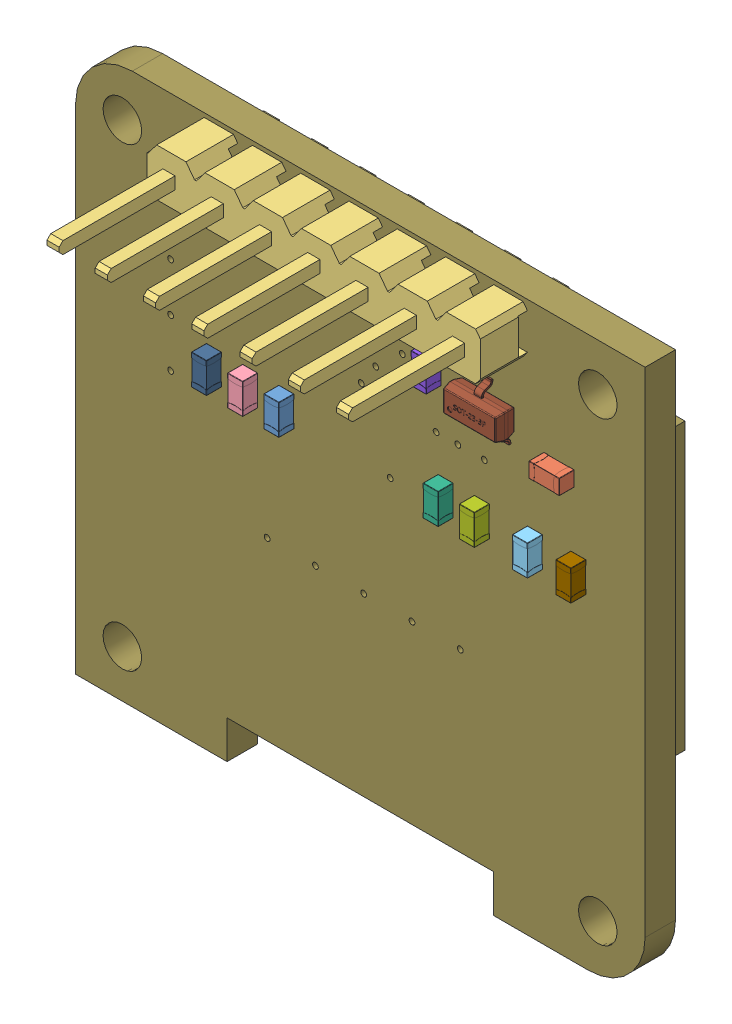
SolidWorks assembly OLED, configuration 默认. Lengths in mm.
Overall size (29.97 28.97 13.2).
35 component instances, 12 part files, 0 mates.
Components (placement in the parent):
- 3D_PCB_7针SPI_2022-02-05_2022-02-05(2)^OLED-1: 3D_PCB_7针SPI_2022-02-05_2022-02-05(2)^OLED [默认] at origin size (29.97 28.97 13.2) (virtual)
  - R5(2)^3D_PCB_7针SPI_2022-02-05_2022-02-05(2)_OLED-1: R5(2)^3D_PCB_7针SPI_2022-02-05_2022-02-05(2)_OLED [默认] at (11.176 -11.303 1.6) x (0 -1 0) z (0 0 1) size (1.6 0.8 0.8) (virtual)
    - R0603^R5(2)_3D_PCB_7针SPI_2022-02-05_2022-02-05(2)_OLED-1: R0603^R5(2)_3D_PCB_7针SPI_2022-02-05_2022-02-05(2)_OLED [默认] at origin size (1.6 0.8 0.8) (virtual)
      - =_[0_1_1_5]^R0603_R5(2)_3D_PCB_7针SPI_2022-02-05_2022-02-05(2)_OLED-1: =_[0_1_1_5]^R0603_R5(2)_3D_PCB_7针SPI_2022-02-05_2022-02-05(2)_OLED [默认] at (0 0 0.4) size (1.6 0.8 0.8) (virtual)
  - R6(2)^3D_PCB_7针SPI_2022-02-05_2022-02-05(2)_OLED-1: R6(2)^3D_PCB_7针SPI_2022-02-05_2022-02-05(2)_OLED [默认] at (25.5271 -6.985 1.6) x (-1 0 0) z (0 0 1) size (1.6 0.8 0.8) (virtual)
    - R0603^R6(2)_3D_PCB_7针SPI_2022-02-05_2022-02-05(2)_OLED-1: R0603^R6(2)_3D_PCB_7针SPI_2022-02-05_2022-02-05(2)_OLED [默认] at origin size (1.6 0.8 0.8) (virtual)
      - =_[0_1_1_5]^R0603_R6(2)_3D_PCB_7针SPI_2022-02-05_2022-02-05(2)_OLED-1: =_[0_1_1_5]^R0603_R6(2)_3D_PCB_7针SPI_2022-02-05_2022-02-05(2)_OLED [默认] at (0 0 0.4) size (1.6 0.8 0.8) (virtual)
  - J1^3D_PCB_7针SPI_2022-02-05_2022-02-05(2)_OLED-1: J1^3D_PCB_7针SPI_2022-02-05_2022-02-05(2)_OLED [默认] at (15.113 -1.524 1.6) size (17.53 2.5 11.6) (virtual)
    - HDR-M-2.54_1X7^J1_3D_PCB_7针SPI_2022-02-05_2022-02-05(2)_OLED-1: HDR-M-2.54_1X7^J1_3D_PCB_7针SPI_2022-02-05_2022-02-05(2)_OLED [默认] at origin size (17.53 2.5 11.6) (virtual)
      - =_[0_1_1_10]^HDR-M-2.54_1X7_J1_3D_PCB_7针SPI_2022-02-05_2022-02-05(2)_OLED-1: =_[0_1_1_10]^HDR-M-2.54_1X7_J1_3D_PCB_7针SPI_2022-02-05_2022-02-05(2)_OLED [默认] at origin size (17.53 2.5 11.6) (virtual)
  - C5(2)^3D_PCB_7针SPI_2022-02-05_2022-02-05(2)_OLED-1: C5(2)^3D_PCB_7针SPI_2022-02-05_2022-02-05(2)_OLED [默认] at (9.271 -11.303 1.6) x (0 -1 0) z (0 0 1) size (1.6 0.8 0.8) (virtual)
    - C0603^C5(2)_3D_PCB_7针SPI_2022-02-05_2022-02-05(2)_OLED-1: C0603^C5(2)_3D_PCB_7针SPI_2022-02-05_2022-02-05(2)_OLED [默认] at origin size (1.6 0.8 0.8) (virtual)
      - =_[0_1_1_14]^C0603_C5(2)_3D_PCB_7针SPI_2022-02-05_2022-02-05(2)_OLED-1: =_[0_1_1_14]^C0603_C5(2)_3D_PCB_7针SPI_2022-02-05_2022-02-05(2)_OLED [默认] at (0 0 0.4) size (1.6 0.8 0.8) (virtual)
  - C2(2)^3D_PCB_7针SPI_2022-02-05_2022-02-05(2)_OLED-1: C2(2)^3D_PCB_7针SPI_2022-02-05_2022-02-05(2)_OLED [默认] at (24.257 -11.176 1.6) x (0 -1 0) z (0 0 1) size (1.6 0.8 0.8) (virtual)
    - C0603^C2(2)_3D_PCB_7针SPI_2022-02-05_2022-02-05(2)_OLED-1: C0603^C2(2)_3D_PCB_7针SPI_2022-02-05_2022-02-05(2)_OLED [默认] at origin size (1.6 0.8 0.8) (virtual)
      - =_[0_1_1_14]^C0603_C2(2)_3D_PCB_7针SPI_2022-02-05_2022-02-05(2)_OLED-1: =_[0_1_1_14]^C0603_C2(2)_3D_PCB_7针SPI_2022-02-05_2022-02-05(2)_OLED [默认] at (0 0 0.4) size (1.6 0.8 0.8) (virtual)
  - C3(2)^3D_PCB_7针SPI_2022-02-05_2022-02-05(2)_OLED-1: C3(2)^3D_PCB_7针SPI_2022-02-05_2022-02-05(2)_OLED [默认] at (19.558 -11.176 1.6) x (0 1 0) z (0 0 1) size (1.6 0.8 0.8) (virtual)
    - C0603^C3(2)_3D_PCB_7针SPI_2022-02-05_2022-02-05(2)_OLED-1: C0603^C3(2)_3D_PCB_7针SPI_2022-02-05_2022-02-05(2)_OLED [默认] at origin size (1.6 0.8 0.8) (virtual)
      - =_[0_1_1_14]^C0603_C3(2)_3D_PCB_7针SPI_2022-02-05_2022-02-05(2)_OLED-1: =_[0_1_1_14]^C0603_C3(2)_3D_PCB_7针SPI_2022-02-05_2022-02-05(2)_OLED [默认] at (0 0 0.4) size (1.6 0.8 0.8) (virtual)
  - C4(2)^3D_PCB_7针SPI_2022-02-05_2022-02-05(2)_OLED-1: C4(2)^3D_PCB_7针SPI_2022-02-05_2022-02-05(2)_OLED [默认] at (21.463 -11.176 1.6) x (0 1 0) z (0 0 1) size (1.6 0.8 0.8) (virtual)
    - C0603^C4(2)_3D_PCB_7针SPI_2022-02-05_2022-02-05(2)_OLED-1: C0603^C4(2)_3D_PCB_7针SPI_2022-02-05_2022-02-05(2)_OLED [默认] at origin size (1.6 0.8 0.8) (virtual)
      - =_[0_1_1_14]^C0603_C4(2)_3D_PCB_7针SPI_2022-02-05_2022-02-05(2)_OLED-1: =_[0_1_1_14]^C0603_C4(2)_3D_PCB_7针SPI_2022-02-05_2022-02-05(2)_OLED [默认] at (0 0 0.4) size (1.6 0.8 0.8) (virtual)
  - C7(2)^3D_PCB_7针SPI_2022-02-05_2022-02-05(2)_OLED-1: C7(2)^3D_PCB_7针SPI_2022-02-05_2022-02-05(2)_OLED [默认] at (18.923 -5.461 1.6) x (0 -1 0) z (0 0 1) size (1.6 0.8 0.8) (virtual)
    - C0603^C7(2)_3D_PCB_7针SPI_2022-02-05_2022-02-05(2)_OLED-1: C0603^C7(2)_3D_PCB_7针SPI_2022-02-05_2022-02-05(2)_OLED [默认] at origin size (1.6 0.8 0.8) (virtual)
      - =_[0_1_1_14]^C0603_C7(2)_3D_PCB_7针SPI_2022-02-05_2022-02-05(2)_OLED-1: =_[0_1_1_14]^C0603_C7(2)_3D_PCB_7针SPI_2022-02-05_2022-02-05(2)_OLED [默认] at (0 0 0.4) size (1.6 0.8 0.8) (virtual)
  - C1(2)^3D_PCB_7针SPI_2022-02-05_2022-02-05(2)_OLED-1: C1(2)^3D_PCB_7针SPI_2022-02-05_2022-02-05(2)_OLED [默认] at (26.5431 -11.176 1.6) x (0 -1 0) z (0 0 1) size (1.6 0.8 0.8) (virtual)
    - C0603^C1(2)_3D_PCB_7针SPI_2022-02-05_2022-02-05(2)_OLED-1: C0603^C1(2)_3D_PCB_7针SPI_2022-02-05_2022-02-05(2)_OLED [默认] at origin size (1.6 0.8 0.8) (virtual)
      - =_[0_1_1_14]^C0603_C1(2)_3D_PCB_7针SPI_2022-02-05_2022-02-05(2)_OLED-1: =_[0_1_1_14]^C0603_C1(2)_3D_PCB_7针SPI_2022-02-05_2022-02-05(2)_OLED [默认] at (0 0 0.4) size (1.6 0.8 0.8) (virtual)
  - C6(2)^3D_PCB_7针SPI_2022-02-05_2022-02-05(2)_OLED-1: C6(2)^3D_PCB_7针SPI_2022-02-05_2022-02-05(2)_OLED [默认] at (7.366 -11.303 1.6) x (0 -1 0) z (0 0 1) size (1.6 0.8 0.8) (virtual)
    - C0603^C6(2)_3D_PCB_7针SPI_2022-02-05_2022-02-05(2)_OLED-1: C0603^C6(2)_3D_PCB_7针SPI_2022-02-05_2022-02-05(2)_OLED [默认] at origin size (1.6 0.8 0.8) (virtual)
      - =_[0_1_1_14]^C0603_C6(2)_3D_PCB_7针SPI_2022-02-05_2022-02-05(2)_OLED-1: =_[0_1_1_14]^C0603_C6(2)_3D_PCB_7针SPI_2022-02-05_2022-02-05(2)_OLED [默认] at (0 0 0.4) size (1.6 0.8 0.8) (virtual)
  - U1(2)^3D_PCB_7针SPI_2022-02-05_2022-02-05(2)_OLED-1: U1(2)^3D_PCB_7针SPI_2022-02-05_2022-02-05(2)_OLED [默认] at (21.844 -5.842 1.6) x (0 -1 0) z (0 0 1) size (2.5 2.89 1.05) (virtual)
    - SOT-23-3_L2.9-W1.3-P1.90-LS2.4-BR^U1(2)_3D_PCB_7针SPI_2022-02-05_2022-02-05(2)_OLED-1: SOT-23-3_L2.9-W1.3-P1.90-LS2.4-BR^U1(2)_3D_PCB_7针SPI_2022-02-05_2022-02-05(2)_OLED [默认] at origin size (2.5 2.89 1.05) (virtual)
      - COMPOUND(2)^SOT-23-3_L2.9-W1.3-P1.90-LS2.4-BR_U1(2)_3D_PCB_7针SPI_2022-02-05_2022-02-05(2)_OLED-1: COMPOUND(2)^SOT-23-3_L2.9-W1.3-P1.90-LS2.4-BR_U1(2)_3D_PCB_7针SPI_2022-02-05_2022-02-05(2)_OLED [默认] at origin size (2.5 2.89 1.05) (virtual)
  - COMPOUND-0^3D_PCB_7针SPI_2022-02-05_2022-02-05(2)_OLED-1: COMPOUND-0^3D_PCB_7针SPI_2022-02-05_2022-02-05(2)_OLED [默认] at origin size (29.97 28.97 4.6) (virtual)
